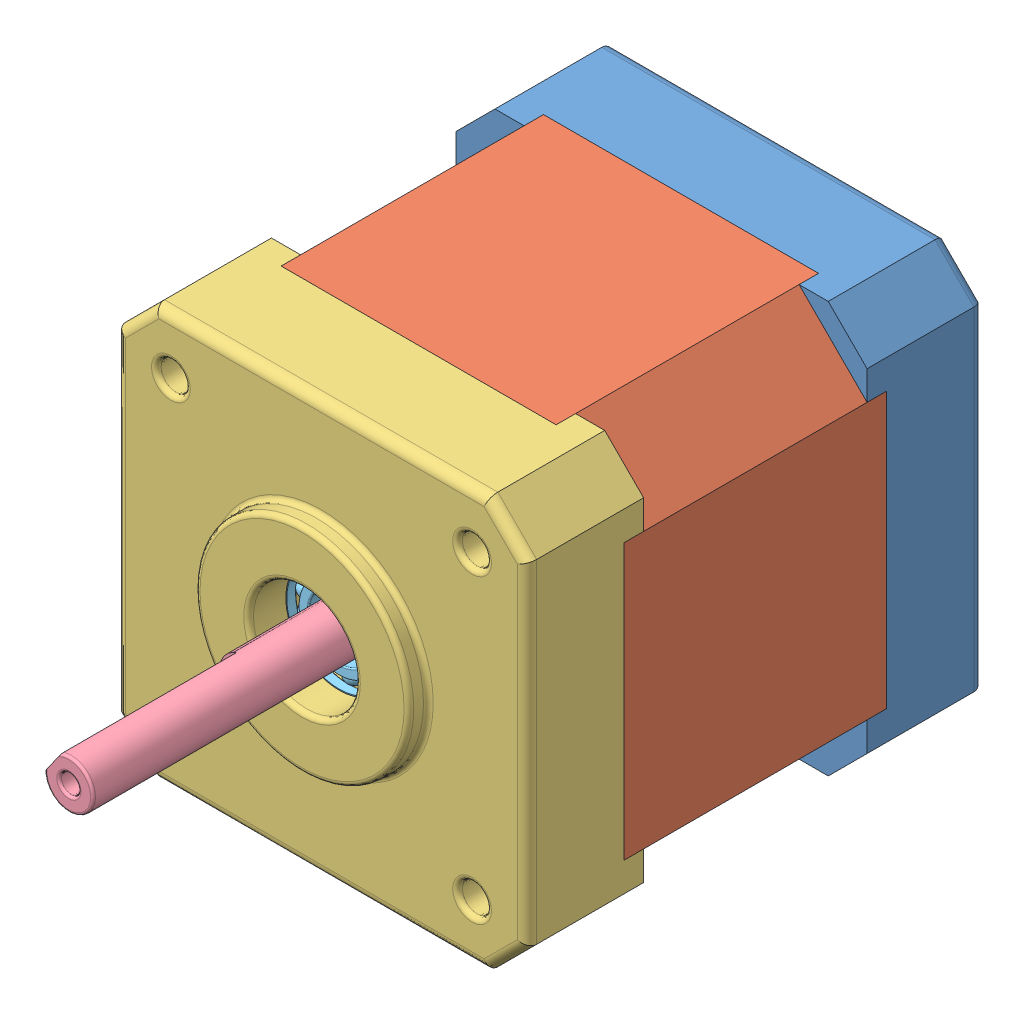
SolidWorks assembly 40MM_NEMA17, configuration Predeterminado. Lengths in mm.
Overall size (58.62 58.81 77.49).
10 component instances, 6 part files, 21 mates.
Components (placement in the parent):
- Base-1: Base [Predeterminado] at (-10.3955 4.6172 0) size (42.3 42.3 12)
- Body1-1: Body1 [Predeterminado] at (-10.3955 4.6172 10) size (42.3 42.3 27)
- FaceCap-1: FaceCap [Predeterminado] at (-10.3955 4.6172 47) x (-1 0 0) z (0 0 -1) size (42.3 42.3 14)
- pan cross head_am-1: pan cross head_am [PreviewCfg] at (5.1045 20.1172 -4.5) x (0 0 1) z (-0.896 0.444054 0) size (47.45 20 20) (hidden)
- pan cross head_am-2: pan cross head_am [PreviewCfg] at (-25.8955 20.1172 -4.5) x (0 0 1) z (-0.859432 0.51125 0) size (47.45 20 20) (hidden)
- pan cross head_am-3: pan cross head_am [PreviewCfg] at (-25.8955 -10.8828 -4.5) x (0 0 1) z (-0.650632 -0.759393 0) size (47.45 20 20) (hidden)
- pan cross head_am-4: pan cross head_am [PreviewCfg] at (5.1045 -10.8828 -4.5) x (0 0 1) z (-0.883632 0.468182 0) size (47.45 20 20) (hidden)
- Shaft1-1: Shaft1 [Predeterminado] at (-10.3955 4.6172 0) x (0.574856 0.818255 0) z (0 0 1) size (5 5 73.04)
- instrument ball bearing_68_am-2: instrument ball bearing_68_am [PreviewCfg] at (-10.3955 4.6172 43.5875) x (0 0 -1) z (0.977058 -0.212972 0) size (3.17 12.7 12.7)
- instrument ball bearing_68_am-4: instrument ball bearing_68_am [PreviewCfg] at (-10.3955 4.6172 3.4125) x (0 0 1) z (-0.460658 -0.887578 0) size (3.17 12.7 12.7)
Mates (geometry in assembly coordinates):
- Paralelo1: parallel anti-aligned: plane of Base-1 through (-10.3955 4.6172 10) normal (0 0 1); plane of Body1-1 through (-10.3955 4.6172 10) normal (0 0 -1)
- Coincidente2: coincident aligned: plane of Base-1 through (-27.5455 25.7672 12) normal (0 1 0); plane of Body1-1 through (-24.5455 25.7672 37) normal (0 1 0)
- Coincidente3: coincident aligned: plane of Base-1 through (-31.5455 21.7672 12) normal (-1 0 0); plane of Body1-1 through (-31.5455 18.7672 37) normal (-1 0 0)
- Coincidente4: coincident anti-aligned: plane of Base-1 through (-10.3955 4.6172 10) normal (0 0 1); plane of Body1-1 through (-10.3955 4.6172 10) normal (0 0 -1)
- Coincidente5: coincident anti-aligned: plane of Body1-1 through (-10.3955 4.6172 37) normal (0 0 1); plane of FaceCap-1 through (-10.3955 4.6172 37) normal (0 0 -1)
- Coincidente6: coincident aligned: plane of Body1-1 through (-31.5455 18.7672 37) normal (-1 0 0); plane of FaceCap-1 through (-31.5455 21.7672 35) normal (-1 0 0)
- Coincidente7: coincident aligned: plane of Body1-1 through (-24.5455 25.7672 37) normal (0 1 0); plane of FaceCap-1 through (6.7545 25.7672 35) normal (0 1 0)
- Concéntrica5: concentric aligned: cylinder of Base-1 through (5.1045 20.1172 22) axis (0 0 -1) radius 1.5; cylinder of pan cross head_am-1 through (5.1045 20.1172 -29.9) axis (0 0 -1) radius 5
- Coincidente8: coincident anti-aligned: plane of Base-1 through (5.1045 20.1172 3) normal (0 0 -1); plane of pan cross head_am-1 through (7.3248 24.5972 3) normal (0 0 1)
- Concéntrica6: concentric aligned: cylinder of Base-1 through (-25.8955 20.1172 22) axis (0 0 -1) radius 1.5; cylinder of pan cross head_am-2 through (-25.8955 20.1172 -29.9) axis (0 0 -1) radius 5
- Concéntrica7: concentric aligned: cylinder of Base-1 through (-25.8955 -10.8828 22) axis (0 0 -1) radius 1.5; cylinder of pan cross head_am-3 through (-25.8955 -10.8828 -29.9) axis (0 0 -1) radius 5
- Concéntrica8: concentric aligned: cylinder of Base-1 through (5.1045 -10.8828 22) axis (0 0 -1) radius 1.5; cylinder of pan cross head_am-4 through (5.1045 -10.8828 -29.9) axis (0 0 -1) radius 5
- Coincidente9: coincident anti-aligned: circle of Base-1; plane of pan cross head_am-3 through (-29.6925 -7.6297 3) normal (0 0 1)
- Coincidente10: coincident anti-aligned: plane of Base-1 through (5.1045 -10.8828 3) normal (0 0 -1); plane of pan cross head_am-4 through (7.4454 -6.4647 3) normal (0 0 1)
- Coincidente11: coincident anti-aligned: plane of Base-1 through (-25.8955 20.1172 3) normal (0 0 -1); plane of pan cross head_am-2 through (-23.3393 24.4143 3) normal (0 0 1)
- Concéntrica10: concentric aligned: cylinder of Base-1 through (-10.3955 4.6172 22) axis (0 0 -1) radius 2.5; cylinder of Shaft1-1 through (-10.3955 4.6172 73) axis (0 0 -1) radius 2.5
- Concéntrica14: concentric aligned: cylinder of Shaft1-1 through (-10.3955 4.6172 73) axis (0 0 -1) radius 2.5; cylinder of instrument ball bearing_68_am-2 through (-10.3955 4.6172 64.225) axis (0 0 -1) radius 3.175
- Concéntrica15: concentric anti-aligned: cylinder of Shaft1-1 through (-10.3955 4.6172 73) axis (0 0 -1) radius 2.5; cylinder of instrument ball bearing_68_am-4 through (-10.3955 4.6172 -17.225) axis (0 0 1) radius 6.35
- Coincidente12: coincident aligned: plane of Base-1 through (-10.3955 4.6172 0) normal (0 0 -1); plane of Shaft1-1 through (-10.3955 4.6172 0) normal (0 0 -1)
- Coincident1: coincident anti-aligned: plane of FaceCap-1 through (-10.3955 4.6172 42) normal (0 0 1); plane of instrument ball bearing_68_am-2 through (-9.6923 7.8434 42) normal (0 0 -1)
- Coincident2: coincident anti-aligned: plane of Base-1 through (-10.3955 4.6172 5) normal (0 0 -1); plane of instrument ball bearing_68_am-4 through (-13.3263 6.1382 5) normal (0 0 1)
